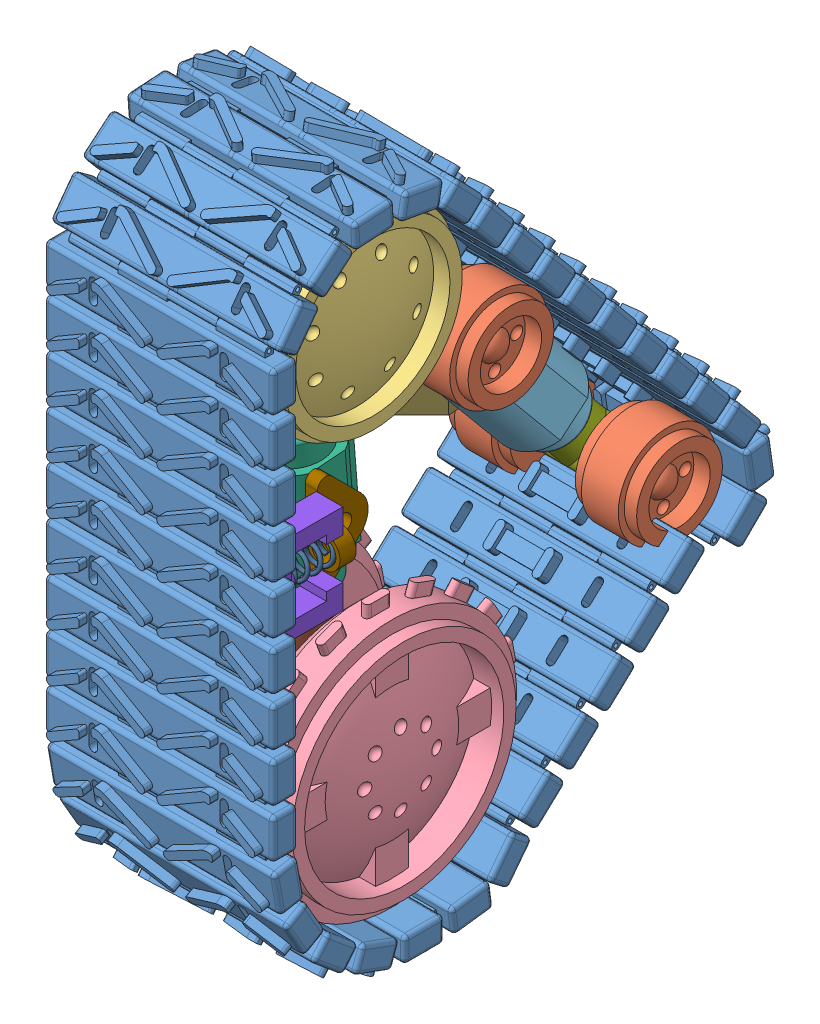
SolidWorks assembly Left Side Drive Train, configuration Default. Lengths in mm.
Overall size (45.17 135.44 102.97).
53 component instances, 12 part files, 147 mates.
Components (placement in the parent):
- Track segment-1: Track segment [Default] at origin size (45.17 8.87 11.14)
- Track segment-2: Track segment [Default] at (0 1.7763 10.0644) x (1 0 0) z (0 0.34232 0.939583) size (45.17 8.87 11.14)
- Track segment-3: Track segment [Default] at (0 34.1905 29.8413) x (1 0 0) z (0 1 0) size (45.17 8.87 11.14)
- Track segment-4: Track segment [Default] at (0 43.7144 29.8413) x (1 0 0) z (0 1 0) size (45.17 8.87 11.14)
- Track segment-5: Track segment [Default] at (0 53.2383 29.8413) x (1 0 0) z (0 1 0) size (45.17 8.87 11.14)
- Track segment-6: Track segment [Default] at (0 6.8872 18.9134) x (1 0 0) z (0 0.642788 0.766044) size (45.17 8.87 11.14)
- Track segment-7: Track segment [Default] at (0 14.7157 25.4824) x (1 0 0) z (0 0.866025 0.5) size (45.17 8.87 11.14)
- Track segment-8: Track segment [Default] at (0 24.3188 28.9776) x (1 0 0) z (0 0.984808 0.173648) size (45.17 8.87 11.14)
- Track segment-9: Track segment [Default] at (0 62.7622 29.8413) x (1 0 0) z (0 1 0) size (45.17 8.87 11.14)
- Track segment-10: Track segment [Default] at (0 72.2861 29.8413) x (1 0 0) z (0 1 0) size (45.17 8.87 11.14)
- Track segment-11: Track segment [Default] at (0 81.81 29.8413) x (1 0 0) z (0 1 0) size (45.17 8.87 11.14)
- Track segment-12: Track segment [Default] at (0 91.3339 29.8413) x (1 0 0) z (0 1 0) size (45.17 8.87 11.14)
- Track segment-13: Track segment [Default] at (0 100.8578 29.8413) x (1 0 0) z (0 1 0) size (45.17 8.87 11.14)
- Track segment-14: Track segment [Default] at (0 110.3817 29.8413) x (1 0 0) z (0 1 0) size (45.17 8.87 11.14)
- Track segment-15: Track segment [Default] at (0 127.7384 19.6963) x (1 0 0) z (0 0.642298 -0.766455) size (45.17 8.87 11.14)
- Track segment-16: Track segment [Default] at (0 131.6664 9.8979) x (1 0 0) z (0 0.064998 -0.997885) size (45.17 8.87 11.14)
- Track segment-17: Track segment [Default] at (0 131.1108 -0.123) x (1 0 0) z (0 -0.174908 -0.984585) size (45.17 8.87 11.14)
- Track segment-18: Track segment [Default] at (0 126.1238 -9.4271) x (1 0 0) z (0 -0.723087 -0.690757) size (45.17 8.87 11.14)
- Track segment-19: Track segment [Default] at (0 118.8782 -15.8648) x (1 0 0) z (0 -0.771041 -0.636786) size (45.17 8.87 11.14)
- Track segment-20: Track segment [Default] at (0 111.5349 -21.9295) x (1 0 0) z (0 -0.771041 -0.636786) size (45.17 8.87 11.14)
- Track segment-21: Track segment [Default] at (0 82.1919 -46.2013) x (1 0 0) z (0 -0.767095 -0.641534) size (45.17 8.87 11.14)
- Track segment-22: Track segment [Default] at (0 120.4147 26.5585) x (1 0 0) z (0 0.806583 -0.591121) size (45.17 8.87 11.14)
- Track segment-23: Track segment [Default] at (0 38.6295 -53.0201) x (1 0 0) z (0 -0.681845 0.731497) size (45.17 8.87 11.14)
- Track segment-24: Track segment [Default] at (0 104.1916 -27.9942) x (1 0 0) z (0 -0.771041 -0.636786) size (45.17 8.87 11.14)
- Track segment-25: Track segment [Default] at (0 96.8483 -34.0588) x (1 0 0) z (0 -0.77104 -0.636786) size (45.17 8.87 11.14)
- Track segment-26: Track segment [Default] at (0 89.505 -40.1235) x (1 0 0) z (0 -0.77104 -0.636786) size (45.17 8.87 11.14)
- Track segment-27: Track segment [Default] at (0 74.8862 -52.3112) x (1 0 0) z (0 -0.767095 -0.641534) size (45.17 8.87 11.14)
- Track segment-28: Track segment [Default] at (0 67.5805 -58.4211) x (1 0 0) z (0 -0.767095 -0.641534) size (45.17 8.87 11.14)
- Track segment-29: Track segment [Default] at (0 60.2747 -64.531) x (1 0 0) z (0 -0.767095 -0.641534) size (45.17 8.87 11.14)
- Track segment-30: Track segment [Default] at (0 50.7132 -68.8203) x (1 0 0) z (0 -0.989231 -0.146359) size (45.17 8.87 11.14)
- Track segment-31: Track segment [Default] at (0 40.5787 -65.4426) x (1 0 0) z (0 -0.703629 0.710567) size (45.17 8.87 11.14)
- Track segment-32: Track segment [Default] at (0 32.1357 -46.0534) x (1 0 0) z (0 -0.681845 0.731497) size (45.17 8.87 11.14)
- Track segment-33: Track segment [Default] at (0 19.148 -32.12) x (1 0 0) z (0 -0.681845 0.731497) size (45.17 8.87 11.14)
- Track segment-34: Track segment [Default] at (0 25.6419 -39.0867) x (1 0 0) z (0 -0.681845 0.731497) size (45.17 8.87 11.14)
- Track segment-35: Track segment [Default] at (0 12.6542 -25.1533) x (1 0 0) z (0 -0.681845 0.731497) size (45.17 8.87 11.14)
- Track segment-36: Track segment [Default] at (0 5.9282 -19.0309) x (1 0 0) z (0 -0.792205 0.610255) size (45.17 8.87 11.14)
- Track segment-37: Track segment [Default] at (0 0.6261 -9.7932) x (1 0 0) z (0 -0.127344 0.991859) size (45.17 8.87 11.14)
- Tensioner Small-1: Tensioner Small [Default] at (-12.5006 89.8246 -21.0494) x (0 -0.325213 -0.945641) z (-1 0 0) size (19.33 19.33 12.1)
- Tensioner Large-1: Tensioner Large [Default] at (12.4939 108.1911 6.1736) x (0 -0.888344 -0.459179) z (1 0 0) size (37.66 37.66 12.1)
- Drive Sprocket-1: Drive Sprocket [Default] at (12.907 29.4005 0) x (0 0 1) z (1 0 0) size (53.82 53.8 11.29)
- Cylinder Small-1: Cylinder Small [Default] at (0.0013 68.7945 -38.5642) x (0 -0.768404 -0.639964) z (-1 0 0) size (29.03 16.13 14.52)
- Cylinder Large-1: Cylinder Large [Default] at (0.0013 68.7945 3.0867) x (0 -0.996944 -0.078115) z (1 0 0) size (29.03 17.74 14.52)
- Axle short-1: Axle short [Default] at (0.0013 69.8778 -37.6621) x (0 0.768404 0.639964) z (-1 0 0) size (61.59 9.68 12.1)
- Shock Absorber Guide-1: Shock Absorber Guide [Default] at (10.4864 68.7945 17.1387) x (0 -1 0) z (1 0 0) size (25.81 15.73 9.28)
- Shock Absorber Pivot-1: Shock Absorber Pivot [Default] at (9.6812 68.7945 3.0867) x (0 -1 0) z (1 0 0) size (19.38 11.58 8.47)
- Shock Absorber Spring-1: Shock Absorber Spring [Default] at (12.5031 68.7945 20.9691) x (0.879385 -0.476111 0) z (0.476111 0.879385 0) size (5.09 14.18 4.84)
- Tensioner Small-2: Tensioner Small [Default] at (12.5031 89.8246 -21.0494) x (0 -1 0.00019) z (1 0 0) size (19.33 19.33 12.1)
- Tensioner Large-2: Tensioner Large [Default] at (-12.4914 108.1911 6.1736) x (0 -0.876526 0.481354) z (-1 0 0) size (37.66 37.66 12.1)
- Drive Sprocket-2: Drive Sprocket [Default] at (-12.9045 29.4005 0) x (0 0 1) z (-1 0 0) size (53.82 53.8 11.29)
- Tensioner Small-3: Tensioner Small [Default] at (-12.5006 49.9309 -54.2748) x (0 1 0) z (-1 0 0) size (19.33 19.33 12.1)
- Tensioner Small-4: Tensioner Small [Default] at (12.5031 49.9309 -54.2748) x (0 -1 0) z (1 0 0) size (19.33 19.33 12.1)
- Axle long-1: Axle long [Default] at (0.0013 68.7958 3.0868) x (0 -0.996944 -0.078115) z (1 0 0) size (90.32 12.9 13.71)
- Bracket-2: Bracket [Default] at (-12.0968 68.7945 -17.7388) x (0 -1 0) z (1 0 0) size (17.74 48.1 9.68)
Mates (geometry in assembly coordinates):
- Concentric61: concentric: cylinder of assembly; cylinder of assembly; cylinder of Track segment-1 through (-9.6774 2.4194 4.7619) axis (1 0 0) radius 0.4039; cylinder of Track segment-2 through (-9.6774 2.4194 4.7619) axis (-1 0 0) radius 0.4039
- Coincident54: coincident: plane of assembly; plane of assembly; plane of Track segment-1 through (-9.6774 2.4194 4.7619) normal (-1 0 0); plane of Track segment-2 through (-9.6774 2.4194 4.7619) normal (1 0 0)
- Perpendicular2: perpendicular: plane of assembly; plane of assembly; plane of Track segment-1 through (0 0 0) normal (0 -1 0); plane of Track segment-3 through (0 34.1905 29.8413) normal (0 0 1)
- Concentric106: concentric: cylinder of assembly; cylinder of assembly; cylinder of Track segment-1 through (-9.6774 2.4193 -4.7619) axis (-1 0 0) radius 0.4039; cylinder of Track segment-37 through (-9.6774 2.4193 -4.7619) axis (1 0 0) radius 0.4039
- Coincident103: coincident: plane of assembly; plane of assembly; plane of Track segment-1 through (9.6774 2.4193 -4.7619) normal (1 0 0); plane of Track segment-37 through (9.6774 2.4193 -4.7619) normal (-1 0 0)
- Concentric62: concentric: cylinder of assembly; cylinder of assembly; cylinder of Track segment-2 through (-9.6774 5.6796 13.7104) axis (1 0 0) radius 0.4039; cylinder of Track segment-6 through (-9.6774 5.6796 13.7104) axis (-1 0 0) radius 0.4039
- Coincident56: coincident: plane of Track segment-2 through (0 5.6796 13.7104) normal (1 0 0); plane of Track segment-6 through (0 5.6796 13.7104) normal (-1 0 0)
- Concentric66: concentric: cylinder of assembly; cylinder of assembly; cylinder of Track segment-3 through (-9.6774 29.4286 27.4219) axis (-1 0 0) radius 0.4039; cylinder of Track segment-8 through (-9.6774 29.4286 27.4219) axis (1 0 0) radius 0.4039
- Coincident61: coincident: plane of Track segment-3 through (-9.6774 29.4286 27.4219) normal (1 0 0); plane of Track segment-8 through (-9.6774 29.4286 27.4219) normal (-1 0 0)
- Concentric68: concentric: cylinder of assembly; cylinder of assembly; cylinder of Track segment-3 through (-9.6774 38.9525 27.4219) axis (1 0 0) radius 0.4039; cylinder of Track segment-4 through (-9.6774 38.9525 27.4219) axis (-1 0 0) radius 0.4039
- Coincident62: coincident: plane of Track segment-3 through (0 38.9525 27.4219) normal (1 0 0); plane of Track segment-4 through (0 38.9525 27.4219) normal (-1 0 0)
- Concentric70: concentric: cylinder of Track segment-4 through (9.6774 48.4764 27.4219) axis (1 0 0) radius 0.4039; cylinder of Track segment-5 through (9.6774 48.4764 27.4219) axis (-1 0 0) radius 0.4039
- Coincident67: coincident: plane of Track segment-4 through (-9.6774 48.4764 27.4219) normal (-1 0 0); plane of Track segment-5 through (-9.6774 48.4764 27.4219) normal (1 0 0)
- Concentric71: concentric: cylinder of Track segment-5 through (-9.6774 58.0003 27.4219) axis (1 0 0) radius 0.4039; cylinder of Track segment-9 through (-9.6774 58.0003 27.4219) axis (-1 0 0) radius 0.4039
- Coincident68: coincident: plane of Track segment-5 through (0 58.0003 27.4219) normal (1 0 0); plane of Track segment-9 through (0 58.0003 27.4219) normal (-1 0 0)
- Concentric64: concentric: cylinder of Track segment-6 through (9.6774 11.8014 21.0062) axis (1 0 0) radius 0.4039; cylinder of Track segment-7 through (9.6774 11.8014 21.0062) axis (-1 0 0) radius 0.4039
- Coincident57: coincident: plane of Track segment-6 through (0 11.8014 21.0062) normal (1 0 0); plane of Track segment-7 through (0 11.8014 21.0062) normal (-1 0 0)
- Concentric65: concentric: cylinder of Track segment-7 through (-9.6774 20.0494 25.7681) axis (1 0 0) radius 0.4039; cylinder of Track segment-8 through (-9.6774 20.0494 25.7681) axis (-1 0 0) radius 0.4039
- Coincident59: coincident: plane of Track segment-7 through (0 20.0494 25.7681) normal (1 0 0); plane of Track segment-8 through (0 20.0494 25.7681) normal (-1 0 0)
- Concentric72: concentric: cylinder of Track segment-9 through (-9.6774 67.5242 27.4219) axis (1 0 0) radius 0.4039; cylinder of Track segment-10 through (-9.6774 67.5242 27.4219) axis (-1 0 0) radius 0.4039
- Coincident69: coincident: plane of Track segment-9 through (-9.6774 67.5242 27.4219) normal (-1 0 0); plane of Track segment-10 through (-9.6774 67.5242 27.4219) normal (1 0 0)
- Concentric73: concentric: cylinder of Track segment-10 through (-9.6774 77.0481 27.4219) axis (1 0 0) radius 0.4039; cylinder of Track segment-11 through (9.6774 77.0481 27.4219) axis (-1 0 0) radius 0.4039
- Coincident70: coincident: plane of Track segment-10 through (-9.6774 77.0481 27.4219) normal (-1 0 0); plane of Track segment-11 through (-9.6774 77.0481 27.4219) normal (1 0 0)
- Concentric74: concentric: cylinder of Track segment-11 through (-9.6774 86.572 27.4219) axis (1 0 0) radius 0.4039; cylinder of Track segment-12 through (-9.6774 86.572 27.4219) axis (-1 0 0) radius 0.4039
- Coincident71: coincident: plane of Track segment-11 through (-9.6774 86.572 27.4219) normal (-1 0 0); plane of Track segment-12 through (-9.6774 86.572 27.4219) normal (1 0 0)
- Concentric75: concentric: cylinder of Track segment-12 through (-9.6774 96.0959 27.4219) axis (1 0 0) radius 0.4039; cylinder of Track segment-13 through (-9.6774 96.0959 27.4219) axis (-1 0 0) radius 0.4039
- Coincident72: coincident: plane of Track segment-12 through (-9.6774 96.0959 27.4219) normal (-1 0 0); plane of Track segment-13 through (-9.6774 96.0959 27.4219) normal (1 0 0)
- Concentric76: concentric: cylinder of Track segment-13 through (-9.6774 105.6198 27.4219) axis (1 0 0) radius 0.4039; cylinder of Track segment-14 through (-9.6774 105.6198 27.4219) axis (-1 0 0) radius 0.4039
- Coincident73: coincident: plane of Track segment-13 through (-9.6774 105.6198 27.4219) normal (-1 0 0); plane of Track segment-14 through (-9.6774 105.6198 27.4219) normal (1 0 0)
- Concentric77: concentric: cylinder of Track segment-14 through (-9.6774 115.1437 27.4219) axis (1 0 0) radius 0.4039; cylinder of Track segment-22 through (-9.6774 115.1437 27.4219) axis (-1 0 0) radius 0.4039
- Coincident74: coincident: plane of Track segment-14 through (-9.6774 115.1437 27.4219) normal (-1 0 0); plane of Track segment-22 through (-9.6774 115.1437 27.4219) normal (1 0 0)
- Concentric78: concentric: cylinder of Track segment-15 through (-9.6774 122.8255 21.7922) axis (-1 0 0) radius 0.4039; cylinder of Track segment-22 through (-9.6774 122.8255 21.7922) axis (1 0 0) radius 0.4039
- Coincident75: coincident: plane of Track segment-15 through (-9.6774 122.8255 21.7922) normal (1 0 0); plane of Track segment-22 through (-9.6774 122.8255 21.7922) normal (-1 0 0)
- Concentric79: concentric: cylinder of Track segment-15 through (-9.6774 128.9426 14.4925) axis (1 0 0) radius 0.4039; cylinder of Track segment-16 through (-9.6774 128.9426 14.4925) axis (-1 0 0) radius 0.4039
- Coincident76: coincident: plane of Track segment-15 through (-9.6774 128.9426 14.4925) normal (-1 0 0); plane of Track segment-16 through (-9.6774 128.9426 14.4925) normal (1 0 0)
- Concentric80: concentric: cylinder of Track segment-16 through (-9.6774 129.5617 4.9888) axis (1 0 0) radius 0.4039; cylinder of Track segment-17 through (9.6774 129.5617 4.9888) axis (-1 0 0) radius 0.4039
- Coincident77: coincident: plane of Track segment-16 through (-9.6774 129.5617 4.9888) normal (-1 0 0); plane of Track segment-17 through (-9.6774 129.5617 4.9888) normal (1 0 0)
- Concentric81: concentric: cylinder of Track segment-17 through (9.6774 127.8959 -4.3883) axis (1 0 0) radius 0.4039; cylinder of Track segment-18 through (9.6774 127.8959 -4.3883) axis (-1 0 0) radius 0.4039
- Coincident78: coincident: plane of Track segment-17 through (-9.6774 127.8959 -4.3883) normal (-1 0 0); plane of Track segment-18 through (-9.6774 127.8959 -4.3883) normal (1 0 0)
- Concentric82: concentric: cylinder of Track segment-18 through (9.6774 121.0093 -10.967) axis (1 0 0) radius 0.4039; cylinder of Track segment-19 through (9.6774 121.0093 -10.967) axis (-1 0 0) radius 0.4039
- Coincident79: coincident: plane of Track segment-18 through (9.6774 121.0093 -10.967) normal (-1 0 0); plane of Track segment-19 through (9.6774 121.0093 -10.967) normal (1 0 0)
- Concentric83: concentric: cylinder of Track segment-19 through (9.6774 113.666 -17.0317) axis (1 0 0) radius 0.4039; cylinder of Track segment-20 through (9.6774 113.666 -17.0317) axis (-1 0 0) radius 0.4039
- Coincident80: coincident: plane of Track segment-19 through (9.6774 113.666 -17.0317) normal (-1 0 0); plane of Track segment-20 through (9.6774 113.666 -17.0317) normal (1 0 0)
- Parallel34: parallel: plane of Track segment-19 through (0 118.8782 -15.8648) normal (0 0.636786 -0.771041); plane of Track segment-20 through (0 111.5349 -21.9295) normal (0 0.636786 -0.771041)
- Concentric104: concentric: cylinder of Track segment-20 through (9.6774 106.3226 -23.0964) axis (1 0 0) radius 0.4039; cylinder of Track segment-24 through (9.6774 106.3226 -23.0964) axis (-1 0 0) radius 0.4039
- Coincident102: coincident: plane of Track segment-20 through (0 106.3226 -23.0964) normal (1 0 0); plane of Track segment-24 through (0 106.3226 -23.0964) normal (-1 0 0)
- Coincident88: coincident: plane of assembly; plane of assembly; plane of Track segment-21 through (0 84.2927 -41.2905) normal (-1 0 0); plane of Track segment-26 through (0 84.2927 -41.2905) normal (1 0 0)
- Concentric90: concentric: cylinder of Track segment-21 through (-9.6774 84.2927 -41.2905) axis (-1 0 0) radius 0.4039; cylinder of Track segment-26 through (-9.6774 84.2927 -41.2905) axis (1 0 0) radius 0.4039
- Concentric91: concentric: cylinder of Track segment-21 through (-9.6774 76.987 -47.4004) axis (1 0 0) radius 0.4039; cylinder of Track segment-27 through (-9.6774 76.987 -47.4004) axis (-1 0 0) radius 0.4039
- Coincident89: coincident: plane of Track segment-21 through (0 76.987 -47.4004) normal (1 0 0); plane of Track segment-27 through (0 76.987 -47.4004) normal (-1 0 0)
- Concentric108: concentric: cylinder of assembly; cylinder of assembly; cylinder of Track segment-23 through (-9.6774 37.1523 -47.8871) axis (1 0 0) radius 0.4039; cylinder of Track segment-32 through (-9.6774 37.1523 -47.8871) axis (-1 0 0) radius 0.4039
- Coincident105: coincident: plane of Track segment-23 through (9.6774 37.1523 -47.8871) normal (-1 0 0); plane of Track segment-32 through (9.6774 37.1523 -47.8871) normal (1 0 0)
- Parallel38: parallel: plane of Track segment-23 through (0 38.6295 -53.0201) normal (0 -0.731497 -0.681845); plane of Track segment-32 through (0 32.1357 -46.0534) normal (0 -0.731497 -0.681845)
- Concentric84: concentric: cylinder of Track segment-24 through (-9.6774 98.9793 -29.1611) axis (1 0 0) radius 0.4039; cylinder of Track segment-25 through (-9.6774 98.9793 -29.1611) axis (-1 0 0) radius 0.4039
- Coincident83: coincident: plane of Track segment-24 through (9.6774 98.9793 -29.1611) normal (-1 0 0); plane of Track segment-25 through (9.6774 98.9793 -29.1611) normal (1 0 0)
- Coincident84: coincident: plane of Track segment-25 through (0 91.636 -35.2258) normal (1 0 0); plane of Track segment-26 through (0 91.636 -35.2258) normal (-1 0 0)
- Concentric88: concentric: cylinder of Track segment-25 through (9.6774 91.636 -35.2258) axis (1 0 0) radius 0.4039; cylinder of Track segment-26 through (9.6774 91.636 -35.2258) axis (-1 0 0) radius 0.4039
- Concentric92: concentric: cylinder of Track segment-27 through (-9.6774 69.6812 -53.5103) axis (1 0 0) radius 0.4039; cylinder of Track segment-28 through (-9.6774 69.6812 -53.5103) axis (-1 0 0) radius 0.4039
- Coincident90: coincident: plane of Track segment-27 through (-9.6774 69.6812 -53.5103) normal (-1 0 0); plane of Track segment-28 through (-9.6774 69.6812 -53.5103) normal (1 0 0)
- Concentric94: concentric: cylinder of Track segment-28 through (-9.6774 62.3755 -59.6202) axis (1 0 0) radius 0.4039; cylinder of Track segment-29 through (-9.6774 62.3755 -59.6202) axis (-1 0 0) radius 0.4039
- Coincident91: coincident: plane of Track segment-28 through (-9.6774 62.3755 -59.6202) normal (-1 0 0); plane of Track segment-29 through (-9.6774 62.3755 -59.6202) normal (1 0 0)
- Concentric95: concentric: cylinder of Track segment-29 through (-9.6774 55.0698 -65.7301) axis (1 0 0) radius 0.4039; cylinder of Track segment-30 through (-9.6774 55.0698 -65.7301) axis (-1 0 0) radius 0.4039
- Coincident93: coincident: plane of Track segment-29 through (-9.6774 55.0698 -65.7301) normal (-1 0 0); plane of Track segment-30 through (-9.6774 55.0698 -65.7301) normal (1 0 0)
- Concentric96: concentric: cylinder of Track segment-30 through (-9.6774 45.6484 -67.124) axis (1 0 0) radius 0.4039; cylinder of Track segment-31 through (-9.6774 45.6484 -67.124) axis (-1 0 0) radius 0.4039
- Coincident94: coincident: plane of Track segment-30 through (-9.6774 45.6484 -67.124) normal (-1 0 0); plane of Track segment-31 through (-9.6774 45.6484 -67.124) normal (1 0 0)
- Concentric99: concentric: cylinder of Track segment-32 through (-9.6774 30.6585 -40.9204) axis (1 0 0) radius 0.4039; cylinder of Track segment-34 through (-9.6774 30.6585 -40.9204) axis (-1 0 0) radius 0.4039
- Coincident97: coincident: plane of Track segment-32 through (-9.6774 30.6585 -40.9204) normal (-1 0 0); plane of Track segment-34 through (-9.6774 30.6585 -40.9204) normal (1 0 0)
- Concentric100: concentric: cylinder of Track segment-33 through (-9.6774 24.1647 -33.9537) axis (-1 0 0) radius 0.4039; cylinder of Track segment-34 through (-9.6774 24.1647 -33.9537) axis (1 0 0) radius 0.4039
- Coincident98: coincident: plane of Track segment-33 through (-9.6774 24.1647 -33.9537) normal (1 0 0); plane of Track segment-34 through (-9.6774 24.1647 -33.9537) normal (-1 0 0)
- Concentric101: concentric: cylinder of Track segment-33 through (-9.6774 17.6709 -26.987) axis (1 0 0) radius 0.4039; cylinder of Track segment-35 through (-9.6774 17.6709 -26.987) axis (-1 0 0) radius 0.4039
- Coincident99: coincident: plane of Track segment-33 through (-9.6774 17.6709 -26.987) normal (-1 0 0); plane of Track segment-35 through (-9.6774 17.6709 -26.987) normal (1 0 0)
- Concentric102: concentric: cylinder of Track segment-35 through (9.6774 11.177 -20.0203) axis (1 0 0) radius 0.4039; cylinder of Track segment-36 through (9.6774 11.177 -20.0203) axis (-1 0 0) radius 0.4039
- Coincident100: coincident: plane of Track segment-35 through (0 11.177 -20.0203) normal (1 0 0); plane of Track segment-36 through (0 11.177 -20.0203) normal (-1 0 0)
- Concentric103: concentric: cylinder of Track segment-36 through (9.6774 3.6322 -14.2083) axis (1 0 0) radius 0.4039; cylinder of Track segment-37 through (9.6774 3.6322 -14.2083) axis (-1 0 0) radius 0.4039
- Coincident101: coincident: plane of Track segment-36 through (0 3.6322 -14.2083) normal (1 0 0); plane of Track segment-37 through (0 3.6322 -14.2083) normal (-1 0 0)
- Concentric45: concentric: cylinder of assembly; cylinder of assembly; cylinder of Tensioner Small-1 through (-16.9354 89.8246 -21.0494) axis (-1 0 0) radius 3.2258; cylinder of Tensioner Small-2 through (16.938 89.8246 -21.0494) axis (1 0 0) radius 3.2258
- Distance8: distance = 12.9032 mm: plane of Tensioner Small-1 through (-6.4503 86.7742 -20.0003) normal (1 0 0); plane of Tensioner Small-2 through (6.4529 89.824 -24.2752) normal (-1 0 0)
- Tangent95: tangent: cylinder of Tensioner Small-1 through (-16.9354 89.8246 -21.0494) axis (-1 0 0) radius 9.6647; plane of Track segment-19 through (0 115.797 -12.134) normal (0 -0.636786 0.771041)
- Tangent96: tangent: cylinder of Tensioner Small-1 through (-16.9354 89.8246 -21.0494) axis (-1 0 0) radius 9.6647; plane of Track segment-20 through (0 108.4537 -18.1986) normal (0 -0.636786 0.771041)
- Tangent99: tangent: cylinder of Tensioner Small-1 through (-16.9354 89.8246 -21.0494) axis (-1 0 0) radius 9.6647; plane of Track segment-24 through (0 101.1104 -24.2633) normal (0 -0.636786 0.771041)
- Tangent100: tangent: cylinder of Tensioner Small-1 through (-16.9354 89.8246 -21.0494) axis (-1 0 0) radius 9.6647; plane of Track segment-25 through (0 93.7671 -30.328) normal (0 -0.636786 0.77104)
- Tangent101: tangent: cylinder of Tensioner Small-1 through (-16.9354 89.8246 -21.0494) axis (-1 0 0) radius 9.6647; plane of Track segment-26 through (0 86.4237 -36.3927) normal (0 -0.636786 0.77104)
- Concentric54: concentric: cylinder of assembly; cylinder of assembly; cylinder of Tensioner Large-1 through (18.5429 108.1911 6.1736) axis (1 0 0) radius 3.2304; cylinder of Tensioner Large-2 through (-18.5404 108.1911 6.1736) axis (-1 0 0) radius 3.2304
- Distance12: distance = 12.9032 mm: cone of assembly; cone of assembly; cone of Tensioner Large-2 through (-6.4424 108.1911 6.1736) axis (-1 0 0); cone of Tensioner Large-1 through (6.4449 108.1911 6.1736) axis (1 0 0); cone of assembly; cone of assembly; cone of Tensioner Large-1; cone of Tensioner Large-2
- Parallel25: parallel: cylinder of Tensioner Large-1 through (6.4449 108.1911 6.1736) axis (1 0 0) radius 1570.2717; cylinder of Tensioner Large-2 through (-6.4424 108.1911 6.1736) axis (-1 0 0) radius 1570.2717
- Concentric56: concentric: cylinder of assembly; cylinder of assembly; cylinder of Tensioner Large-1 through (18.5429 108.1911 6.1736) axis (1 0 0) radius 3.2304; cylinder of Axle long-1 through (-6.1874 108.1911 6.1736) axis (1 0 0) radius 3.2258
- Concentric58: concentric: cylinder of assembly; cylinder of assembly; cylinder of Drive Sprocket-1 through (18.5534 29.4005 0) axis (1 0 0) radius 4.8387; cylinder of Drive Sprocket-2 through (-18.5509 29.4005 0) axis (-1 0 0) radius 4.8387; plane of assembly; plane of assembly; plane of Drive Sprocket-1; plane of Drive Sprocket-2; cone of ?
- Parallel27: parallel: plane of Drive Sprocket-1 through (7.2606 24.5618 0) normal (-1 0 0); plane of Drive Sprocket-2 through (-7.258 34.2392 0) normal (1 0 0)
- Distance13: distance = 14.5186 mm: plane of assembly; plane of assembly; plane of Drive Sprocket-1 through (7.2606 24.5618 0) normal (-1 0 0); plane of Drive Sprocket-2 through (-7.258 34.2392 0) normal (1 0 0); cone of ?; plane of assembly; plane of assembly; plane of Drive Sprocket-1; plane of Drive Sprocket-2
- Parallel28: parallel: plane of Drive Sprocket-1 through (12.907 56.2991 1.6129) normal (0 1 0); plane of Drive Sprocket-2 through (-12.9045 56.2991 -1.6129) normal (0 1 0)
- Concentric50: concentric: cylinder of assembly; cylinder of assembly; cylinder of Cylinder Small-1 through (0.0013 79.9488 -29.2745) axis (0 -0.768404 -0.639964) radius 4.8387; cylinder of Axle short-1 through (0.0013 49.9309 -54.2748) axis (0 0.768404 0.639964) radius 4.8387
- Concentric52: concentric: cylinder of Cylinder Large-1 through (0.0013 83.2663 4.2206) axis (0 -0.996944 -0.078115) radius 4.8387; cylinder of Axle long-1 through (0.0013 108.1911 6.1736) axis (0 -0.996944 -0.078115) radius 4.8387
- Parallel26: parallel: plane of Cylinder Large-1 through (-7.258 78.7168 0.3408) normal (-1 0 0); plane of Axle long-1 through (-6.8542 29.4005 0) normal (-1 0 0)
- Distance16: distance = 39.5173 mm: line of Cylinder Large-1 through (-6.049 68.7945 3.0867) axis (-1 0 0); axis of Axle long-1 through (-6.1874 108.1911 6.1736) axis (1 0 0)
- Concentric47: concentric: cylinder of Axle short-1 through (6.0503 89.8246 -21.0494) axis (-1 0 0) radius 3.2258; cylinder of Tensioner Small-2 through (16.938 89.8246 -21.0494) axis (1 0 0) radius 3.2258
- Concentric48: concentric: cylinder of Axle short-1 through (6.0503 49.9309 -54.2748) axis (-1 0 0) radius 3.2258; cylinder of Tensioner Small-4 through (16.938 49.9309 -54.2748) axis (1 0 0) radius 3.2258
- Width23: width: plane of Tensioner Small-4 through (6.4529 49.9309 -57.5006) normal (-1 0 0); plane of Tensioner Small-3 through (-6.4503 49.9309 -57.5006) normal (1 0 0); plane of Axle short-1 through (6.0503 49.9309 -54.2748) normal (1 0 0); plane of Axle short-1 through (-6.0477 49.9309 -54.2748) normal (-1 0 0)
- Width24: width: plane of Tensioner Small-2 through (6.4529 89.824 -24.2752) normal (-1 0 0); plane of Tensioner Small-1 through (-6.4503 86.7742 -20.0003) normal (1 0 0); plane of Axle short-1 through (6.0503 89.8246 -21.0494) normal (1 0 0); plane of Axle short-1 through (-6.0477 89.8246 -21.0494) normal (-1 0 0)
- Concentric113: concentric: cylinder of assembly; cylinder of assembly; cylinder of Shock Absorber Guide-1 through (12.5031 68.7945 20.9691) axis (0 0 -1) radius 2.4206; cylinder of Shock Absorber Pivot-1 through (12.5031 68.7945 7.4072) axis (0 0 1) radius 2.4206; cone of ?; cone of ?; plane of assembly; plane of assembly; cone of ?; plane of ?; plane of ?; cone of ?; cone of ?; cone of ?
- Parallel41: parallel: plane of Shock Absorber Guide-1 through (15.7289 68.7945 17.1387) normal (1 0 0); plane of Shock Absorber Pivot-1 through (9.6812 76.8717 6.602) normal (1 0 0)
- Coincident111: coincident: plane of Shock Absorber Guide-1 through (12.5031 68.7945 20.9691) normal (0 0 -1); plane of Shock Absorber Spring-1 through (12.5031 68.7945 20.9691) normal (0 0 -1)
- Concentric115: concentric: circle of Shock Absorber Guide-1; unknown of Shock Absorber Spring-1
- Coincident112: coincident: plane of Shock Absorber Guide-1 through (15.7289 77.6668 25.0026) normal (0 0 1); plane of Track segment-10 through (0 72.2861 25.0026) normal (0 0 -1)
- Width26: width: plane of Tensioner Large-2 through (-8.8617 117.2545 22.6777) normal (1 0 0); plane of Tensioner Large-1 through (8.8642 116.837 -10.5531) normal (-1 0 0); plane of Axle long-1 through (6.19 108.1911 6.1736) normal (1 0 0); plane of Axle long-1 through (-6.1874 108.1911 6.1736) normal (-1 0 0)
- Tangent82: tangent: cylinder of assembly; plane of assembly; cylinder of Tensioner Large-2 through (-18.5404 108.1911 6.1736) axis (-1 0 0) radius 18.829; plane of Track segment-3 through (0 34.1905 25.0026) normal (0 0 -1)
- Tangent83: tangent: cylinder of Tensioner Large-2 through (-18.5404 108.1911 6.1736) axis (-1 0 0) radius 18.829; plane of Track segment-4 through (0 43.7144 25.0026) normal (0 0 -1)
- Tangent84: tangent: cylinder of Tensioner Large-2 through (-18.5404 108.1911 6.1736) axis (-1 0 0) radius 18.829; plane of Track segment-5 through (0 53.2383 25.0026) normal (0 0 -1)
- Tangent85: tangent: cylinder of Tensioner Large-2 through (-18.5404 108.1911 6.1736) axis (-1 0 0) radius 18.829; plane of Track segment-9 through (0 62.7622 25.0026) normal (0 0 -1)
- Tangent86: tangent: cylinder of Tensioner Large-2 through (-18.5404 108.1911 6.1736) axis (-1 0 0) radius 18.829; plane of Track segment-10 through (0 72.2861 25.0026) normal (0 0 -1)
- Tangent87: tangent: cylinder of Tensioner Large-2 through (-18.5404 108.1911 6.1736) axis (-1 0 0) radius 18.829; plane of Track segment-11 through (0 81.81 25.0026) normal (0 0 -1)
- Tangent88: tangent: cylinder of Tensioner Large-2 through (-18.5404 108.1911 6.1736) axis (-1 0 0) radius 18.829; plane of Track segment-12 through (0 91.3339 25.0026) normal (0 0 -1)
- Tangent89: tangent: cylinder of Tensioner Large-2 through (-18.5404 108.1911 6.1736) axis (-1 0 0) radius 18.829; plane of Track segment-13 through (0 100.8578 25.0026) normal (0 0 -1)
- Tangent90: tangent: cylinder of Tensioner Large-2 through (-18.5404 108.1911 6.1736) axis (-1 0 0) radius 18.829; plane of Track segment-14 through (0 110.3817 25.0026) normal (0 0 -1)
- Tangent91: tangent: cylinder of Tensioner Large-2 through (-18.5404 108.1911 6.1736) axis (-1 0 0) radius 18.829; plane of Track segment-15 through (0 124.0297 16.5884) normal (0 -0.766455 -0.642298)
- Tangent92: tangent: cylinder of Tensioner Large-2 through (-18.5404 108.1911 6.1736) axis (-1 0 0) radius 18.829; plane of Track segment-16 through (0 126.8379 9.5834) normal (0 -0.997885 -0.064998)
- Tangent93: tangent: cylinder of Tensioner Large-2 through (-18.5404 108.1911 6.1736) axis (-1 0 0) radius 18.829; plane of Track segment-17 through (0 126.3467 0.7234) normal (0 -0.984585 0.174908)
- Tangent94: tangent: cylinder of Tensioner Large-2 through (-18.5404 108.1911 6.1736) axis (-1 0 0) radius 18.829; plane of Track segment-18 through (0 122.7814 -5.9283) normal (0 -0.690757 0.723087)
- Tangent98: tangent: cylinder of Tensioner Large-2 through (-18.5404 108.1911 6.1736) axis (-1 0 0) radius 18.829; plane of Track segment-22 through (0 117.5544 22.6556) normal (0 -0.591121 -0.806583)
- Concentric59: concentric: cylinder of Axle long-1 through (-6.8542 29.4005 0) axis (1 0 0) radius 4.8387; cylinder of Drive Sprocket-2 through (-18.5509 29.4005 0) axis (-1 0 0) radius 4.8387
- Width27: width: plane of Drive Sprocket-2 through (-7.258 34.2392 0) normal (1 0 0); plane of Drive Sprocket-1 through (7.2606 24.5618 0) normal (-1 0 0); plane of Axle long-1 through (-6.8542 29.4005 0) normal (-1 0 0); plane of Axle long-1 through (6.8567 29.4005 0) normal (1 0 0)
- Width30: width: plane of Track segment-1 through (-12.098 0 -1.6129) normal (-1 0 0); plane of Track segment-1 through (-13.7109 0 -1.6129) normal (1 0 0); plane of Drive Sprocket-2 through (-13.7122 2.5019 1.6129) normal (-1 0 0); plane of Drive Sprocket-2 through (-12.0968 2.5019 1.6129) normal (1 0 0)
- Tangent80: tangent: cylinder of assembly; plane of assembly; cylinder of Drive Sprocket-2 through (-18.5509 29.4005 0) axis (-1 0 0) radius 24.5618; plane of Track segment-1 through (0 4.8387 0) normal (0 1 0)
- Concentric116: concentric: cylinder of assembly; cylinder of assembly; cylinder of Drive Sprocket-2 through (-12.9045 2.5019 -1.6129) axis (0 1 0) radius 0.8077; cylinder of Track segment-1 through (-12.9045 0 -1.6129) axis (0 1 0) radius 0.8065
- Tangent81: tangent: cylinder of assembly; plane of assembly; cylinder of Drive Sprocket-2 through (-18.5509 29.4005 0) axis (-1 0 0) radius 24.5618; plane of Track segment-2 through (0 6.3226 8.408) normal (0 0.939583 -0.34232); plane of assembly; plane of assembly; plane of Drive Sprocket-2; plane of ?; plane of assembly; plane of assembly; plane of Drive Sprocket-2; plane of ?; plane of assembly; plane of assembly; plane of Drive Sprocket-2; plane of ?
- Parallel45: parallel: plane of Drive Sprocket-2 through (-12.9045 9.8317 18.5256) normal (0 -0.766044 0.642788); plane of Track segment-6 through (-10.889 6.1814 20.5816) normal (0 -0.766044 0.642788)
- Parallel46: parallel: plane of Drive Sprocket-2 through (-12.9045 17.348 24.1013) normal (0 -0.5 0.866025); plane of Track segment-7 through (-10.889 14.6231 27.2913) normal (0 -0.5 0.866025)
- Parallel47: parallel: plane of Drive Sprocket-2 through (-12.9045 26.318 26.77) normal (0 -0.173648 0.984808); plane of Track segment-8 through (-10.889 24.8505 30.7091) normal (0 -0.173648 0.984808)
- Tangent107: tangent: cylinder of Drive Sprocket-2 through (-18.5509 29.4005 0) axis (-1 0 0) radius 24.5618; plane of Track segment-32 through (0 35.6752 -42.7541) normal (0 0.731497 0.681845)
- Tangent108: tangent: cylinder of Drive Sprocket-2 through (-18.5509 29.4005 0) axis (-1 0 0) radius 24.5618; plane of Track segment-33 through (0 22.6875 -28.8207) normal (0 0.731497 0.681845)
- Tangent109: tangent: cylinder of Drive Sprocket-2 through (-18.5509 29.4005 0) axis (-1 0 0) radius 24.5618; plane of Track segment-34 through (0 29.1813 -35.7874) normal (0 0.731497 0.681845)
- Tangent110: tangent: cylinder of Drive Sprocket-2 through (-18.5509 29.4005 0) axis (-1 0 0) radius 24.5618; plane of Track segment-35 through (0 16.1937 -21.854) normal (0 0.731497 0.681845)
- Tangent111: tangent: cylinder of Drive Sprocket-2 through (-18.5509 29.4005 0) axis (-1 0 0) radius 24.5618; plane of Track segment-36 through (0 8.881 -15.1977) normal (0 0.610255 0.792205)
- Concentric46: concentric: cylinder of Tensioner Small-3 through (-16.9354 49.9309 -54.2748) axis (-1 0 0) radius 3.2258; cylinder of Tensioner Small-4 through (16.938 49.9309 -54.2748) axis (1 0 0) radius 3.2258
- Distance9: distance = 12.9032 mm: plane of Tensioner Small-3 through (-6.4503 49.9309 -57.5006) normal (1 0 0); plane of Tensioner Small-4 through (6.4529 49.9309 -57.5006) normal (-1 0 0)
- Tangent97: tangent: cylinder of Tensioner Small-3 through (-16.9354 49.9309 -54.2748) axis (-1 0 0) radius 9.6647; plane of Track segment-21 through (0 79.0877 -42.4895) normal (0 -0.641534 0.767095)
- Tangent102: tangent: cylinder of Tensioner Small-3 through (-16.9354 49.9309 -54.2748) axis (-1 0 0) radius 9.6647; plane of Track segment-27 through (0 71.782 -48.5994) normal (0 -0.641534 0.767095)
- Tangent103: tangent: cylinder of Tensioner Small-3 through (-16.9354 49.9309 -54.2748) axis (-1 0 0) radius 9.6647; plane of Track segment-28 through (0 64.4763 -54.7093) normal (0 -0.641534 0.767095)
- Tangent104: tangent: cylinder of Tensioner Small-3 through (-16.9354 49.9309 -54.2748) axis (-1 0 0) radius 9.6647; plane of Track segment-29 through (0 57.1705 -60.8193) normal (0 -0.641534 0.767095)
- Tangent105: tangent: cylinder of Tensioner Small-3 through (-16.9354 49.9309 -54.2748) axis (-1 0 0) radius 9.6647; plane of Track segment-30 through (0 50.005 -64.0337) normal (0 -0.146359 0.989231)
- Tangent106: tangent: cylinder of Tensioner Small-3 through (-16.9354 49.9309 -54.2748) axis (-1 0 0) radius 9.6647; plane of Track segment-31 through (0 44.0169 -62.038) normal (0 0.710567 0.703629)
- Concentric117: concentric: cylinder of Cylinder Large-1 through (-6.049 68.7945 3.0867) axis (-1 0 0) radius 1.651; cylinder of Bracket-2 through (-16.9354 68.7945 3.0867) axis (1 0 0) radius 1.6129
- Coincident113: coincident: plane of Cylinder Large-1 through (-7.258 78.7168 0.3408) normal (-1 0 0); plane of Bracket-2 through (-7.258 77.6668 6.3125) normal (1 0 0)
- Parallel48: parallel: plane of Drive Sprocket-2 through (-12.9045 56.2991 -1.6129) normal (0 1 0); plane of Bracket-2 through (-12.0968 59.9223 -17.7388) normal (0 -1 0)
- Coincident114: coincident: plane of Cylinder Small-1 through (-7.258 73.9827 -29.6719) normal (-1 0 0); plane of Bracket-2 through (-7.258 77.6668 -41.79) normal (1 0 0)
- Concentric119: concentric: cylinder of Cylinder Small-1 through (-6.049 68.7945 -38.5642) axis (-1 0 0) radius 1.6129; cylinder of Bracket-2 through (-16.9354 68.7945 -38.5642) axis (1 0 0) radius 1.6129
- Coincident115: coincident: plane of Cylinder Large-1 through (7.2606 78.7168 0.3408) normal (1 0 0); plane of Shock Absorber Pivot-1 through (7.2606 76.8717 6.602) normal (-1 0 0)
- Concentric120: concentric: cylinder of Cylinder Large-1 through (6.0515 68.7945 3.0867) axis (1 0 0) radius 1.651; cylinder of Shock Absorber Pivot-1 through (7.2606 68.7945 3.0867) axis (1 0 0) radius 1.6129
